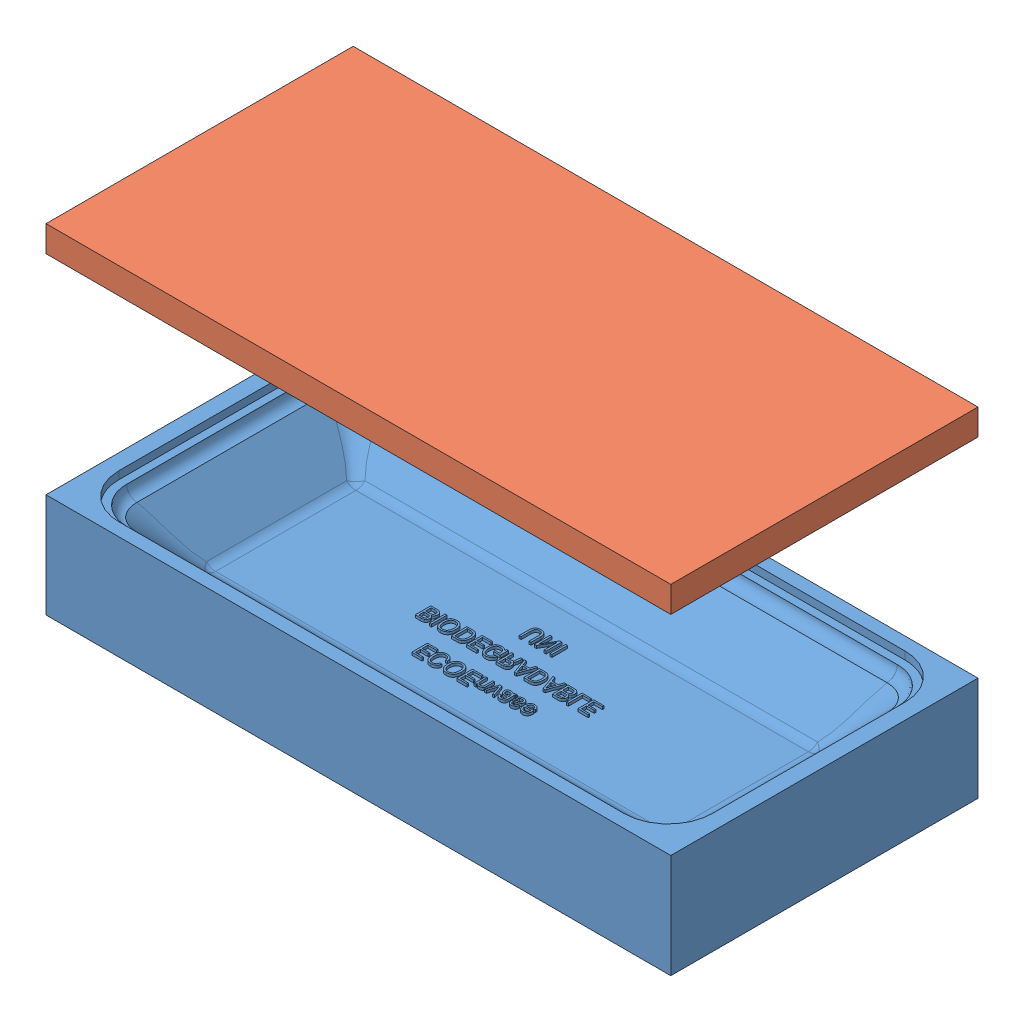
SolidWorks assembly Ensamblaje envase para hotdog, configuration Predeterminado. Lengths in mm.
Overall size (240 130.19 118).
2 component instances, 2 part files, 3 mates.
Components (placement in the parent):
- Barqueta 1 BASE MOLDE-1: Barqueta 1 BASE MOLDE [Predeterminado] at (-54.7607 -7.086 0) size (240 40.06 118)
- Barqueta 1.2 BASE MOLDE SUPERIOR-1: Barqueta 1.2 BASE MOLDE SUPERIOR [Predeterminado] at (-54.7607 73.1044 0) size (240 34.66 118)
Mates (geometry in assembly coordinates):
- Coincidente1: coincident: plane of assembly; plane of assembly; plane of Barqueta 1 BASE MOLDE-1 through (-174.7607 -22.086 -59) normal (-1 0 0); plane of Barqueta 1.2 BASE MOLDE SUPERIOR-1 through (-174.7607 108.1044 59) normal (-1 0 0)
- Coincidente2: coincident: plane of assembly; plane of assembly; plane of Barqueta 1 BASE MOLDE-1 through (-174.7607 -22.086 59) normal (0 0 1); plane of Barqueta 1.2 BASE MOLDE SUPERIOR-1 through (-174.7607 108.1044 59) normal (0 0 1)
- Distancia límite1: limit distance = 80.1904 mm: plane of assembly; plane of assembly; plane of Barqueta 1.2 BASE MOLDE SUPERIOR-1 through (-54.7607 98.1044 0) normal (0 -1 0); plane of Barqueta 1 BASE MOLDE-1 through (54.2771 17.914 -49.0301) normal (0 1 0)
